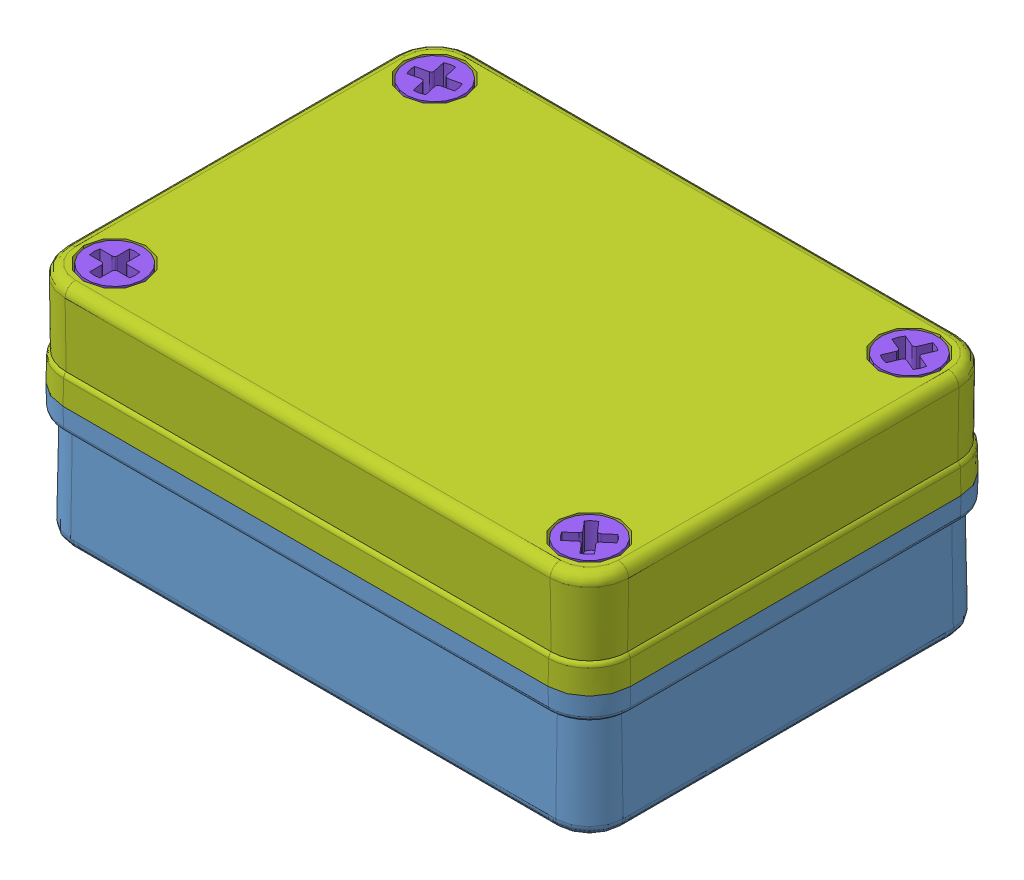
SolidWorks assembly _Adafruit_Feather_enclosure, configuration Default. Lengths in mm.
Overall size (110 46 80).
57 component instances, 26 part files, 18 mates.
Components (placement in the parent):
- KW_1643_bottom-1: KW_1643_bottom [Default] at origin size (110 28.2 80)
- 2926 Terminal Block Breakout FeatherWing-1: 2926 Terminal Block Breakout FeatherWing [Default] at (0 3.215 0) size (67.5 15.2 50.8)
  - 2926 Terminal Block Breakout FeatherWing-1: 2926 Terminal Block Breakout FeatherWing [Default] at origin size (67.5 6.27 50.8)
  - screw_terminal_16x_3.5pitch-1: screw_terminal_16x_3.5pitch [Default] at (-28 1.57 14.4) x (0 0 1) z (-1 0 0) size (7 12.2 56)
  - screw_terminal_16x_3.5pitch-2: screw_terminal_16x_3.5pitch [Default] at (28 1.57 -14.4) x (0 0 -1) z (1 0 0) size (7 12.2 56)
  - header_f16_tall-1: header_f16_tall [Default] at (-20.445 1.57 10.16) size (40.89 14.4 2.5)
  - header_f12_tall-1: header_f12_tall [Default] at (-10.285 1.57 -10.16) size (30.73 14.4 2.5)
- bracket_3D_printed-1: bracket_3D_printed [Default] at (-44.1 1 0) size (15 9.8 54)
- bracket_3D_printed-2: bracket_3D_printed [Default] at (44.1 1 0) x (-1 0 0) z (0 0 -1) size (15 9.8 54)
- KW_1643_top-2: KW_1643_top [Default] at origin size (110 36.5 80)
  - KW_1643_top-1: KW_1643_top [Default] at (0 25 0) x (-1 0 0) z (0 0 1) size (110 21.5 80)
  - KW_1643_screw-1: KW_1643_screw [Default] at (-46 45 -31) x (0.975576 0 -0.219664) z (0.219664 0 0.975576) size (11 36.5 11)
  - KW_1643_screw-2: KW_1643_screw [Default] at (-46 45 31) size (11 36.5 11)
  - KW_1643_screw-3: KW_1643_screw [Default] at (46 45 -31) x (0.38812 0 -0.921609) z (0.921609 0 0.38812) size (11 36.5 11)
  - KW_1643_screw-4: KW_1643_screw [Default] at (46 45 31) x (0.65086 0 0.759198) z (-0.759198 0 0.65086) size (11 36.5 11)
- 3857 Adafruit Feather M4 Express headers-1: 3857 Adafruit Feather M4 Express headers [Default] at (-25.4 18.685 11.43) x (1 0 0) z (0 1 0) size (50.85 22.86 14.87)
  - 3857 Adafruit Feather M4 Express-1: 3857 Adafruit Feather M4 Express [Default] at origin size (50.85 22.86 6.37)
    - 3857 Adafruit Feather M4 Express(2)^3857 Adafruit Feather M4 Express-1: 3857 Adafruit Feather M4 Express(2)^3857 Adafruit Feather M4 Express [Default] at origin size (50.85 22.86 6.37) (virtual)
      - PCB Component^3857 Adafruit Feather M4 Express(2)_3857 Adafruit Feather M4 Express-1: PCB Component^3857 Adafruit Feather M4 Express(2)_3857 Adafruit Feather M4 Express [Default] at origin size (50.85 22.86 6.37) (virtual)
        - Board^PCB Component_3857 Adafruit Feather M4 Express(2)_3857 Adafruit Feather M4 Express-1: Board^PCB Component_3857 Adafruit Feather M4 Express(2)_3857 Adafruit Feather M4 Express [Default] at origin size (50.8 22.86 1.57) (virtual)
        - 10uF^PCB Component_3857 Adafruit Feather M4 Express(2)_3857 Adafruit Feather M4 Express-1: 10uF^PCB Component_3857 Adafruit Feather M4 Express(2)_3857 Adafruit Feather M4 Express [Default] at (12.042 9.838 1.57) x (0 -1 0) z (0 0 1) size (2 1.25 1) (virtual)
        - 10uF^PCB Component_3857 Adafruit Feather M4 Express(2)_3857 Adafruit Feather M4 Express-2: 10uF^PCB Component_3857 Adafruit Feather M4 Express(2)_3857 Adafruit Feather M4 Express [Default] at (14.728 13.858 1.57) size (2 1.25 1) (virtual)
        - 10uF^PCB Component_3857 Adafruit Feather M4 Express(2)_3857 Adafruit Feather M4 Express-3: 10uF^PCB Component_3857 Adafruit Feather M4 Express(2)_3857 Adafruit Feather M4 Express [Default] at (15.748 17.272 1.57) x (0 -1 0) z (0 0 1) size (2 1.25 1) (virtual)
        - 10uF^PCB Component_3857 Adafruit Feather M4 Express(2)_3857 Adafruit Feather M4 Express-4: 10uF^PCB Component_3857 Adafruit Feather M4 Express(2)_3857 Adafruit Feather M4 Express [Default] at (35.065 18.669 1.57) size (2 1.25 1) (virtual)
        - 10uF^PCB Component_3857 Adafruit Feather M4 Express(2)_3857 Adafruit Feather M4 Express-5: 10uF^PCB Component_3857 Adafruit Feather M4 Express(2)_3857 Adafruit Feather M4 Express [Default] at (18.796 11.303 1.57) x (0 -1 0) z (0 0 1) size (2 1.25 1) (virtual)
        - 1uF^PCB Component_3857 Adafruit Feather M4 Express(2)_3857 Adafruit Feather M4 Express-1: 1uF^PCB Component_3857 Adafruit Feather M4 Express(2)_3857 Adafruit Feather M4 Express [Default] at (24.909 17.78 1.57) x (0 1 0) z (0 0 1) size (1.6 0.9 0.8) (virtual)
        - 1uF^PCB Component_3857 Adafruit Feather M4 Express(2)_3857 Adafruit Feather M4 Express-2: 1uF^PCB Component_3857 Adafruit Feather M4 Express(2)_3857 Adafruit Feather M4 Express [Default] at (11.989 4.218 1.57) size (1.6 0.9 0.8) (virtual)
        - 1uF^PCB Component_3857 Adafruit Feather M4 Express(2)_3857 Adafruit Feather M4 Express-3: 1uF^PCB Component_3857 Adafruit Feather M4 Express(2)_3857 Adafruit Feather M4 Express [Default] at (5.715 20.955 1.57) x (0 -1 0) z (0 0 1) size (1.6 0.9 0.8) (virtual)
        - 1uF^PCB Component_3857 Adafruit Feather M4 Express(2)_3857 Adafruit Feather M4 Express-4: 1uF^PCB Component_3857 Adafruit Feather M4 Express(2)_3857 Adafruit Feather M4 Express [Default] at (5.829 4.254 1.57) size (1.6 0.9 0.8) (virtual)
        - 1uF^PCB Component_3857 Adafruit Feather M4 Express(2)_3857 Adafruit Feather M4 Express-5: 1uF^PCB Component_3857 Adafruit Feather M4 Express(2)_3857 Adafruit Feather M4 Express [Default] at (18.415 17.97 1.57) size (1.6 0.9 0.8) (virtual)
        - 1uF^PCB Component_3857 Adafruit Feather M4 Express(2)_3857 Adafruit Feather M4 Express-6: 1uF^PCB Component_3857 Adafruit Feather M4 Express(2)_3857 Adafruit Feather M4 Express [Default] at (19.202 5.067 1.57) x (0 1 0) z (0 0 1) size (1.6 0.9 0.8) (virtual)
        - 1uF^PCB Component_3857 Adafruit Feather M4 Express(2)_3857 Adafruit Feather M4 Express-7: 1uF^PCB Component_3857 Adafruit Feather M4 Express(2)_3857 Adafruit Feather M4 Express [Default] at (21.526 6.35 1.57) x (-1 0 0) z (0 0 1) size (1.6 0.9 0.8) (virtual)
        - 1uF^PCB Component_3857 Adafruit Feather M4 Express(2)_3857 Adafruit Feather M4 Express-8: 1uF^PCB Component_3857 Adafruit Feather M4 Express(2)_3857 Adafruit Feather M4 Express [Default] at (36.119 4.648 1.57) x (-1 0 0) z (0 0 1) size (1.6 0.9 0.8) (virtual)
        - 1uF^PCB Component_3857 Adafruit Feather M4 Express(2)_3857 Adafruit Feather M4 Express-9: 1uF^PCB Component_3857 Adafruit Feather M4 Express(2)_3857 Adafruit Feather M4 Express [Default] at (19.126 8.065 1.57) x (0 1 0) z (0 0 1) size (1.6 0.9 0.8) (virtual)
        - 1uF^PCB Component_3857 Adafruit Feather M4 Express(2)_3857 Adafruit Feather M4 Express-10: 1uF^PCB Component_3857 Adafruit Feather M4 Express(2)_3857 Adafruit Feather M4 Express [Default] at (29.662 5.263 1.57) x (-1 0 0) z (0 0 1) size (1.6 0.9 0.8) (virtual)
        - 1uF^PCB Component_3857 Adafruit Feather M4 Express(2)_3857 Adafruit Feather M4 Express-11: 1uF^PCB Component_3857 Adafruit Feather M4 Express(2)_3857 Adafruit Feather M4 Express [Default] at (8.89 4.254 1.57) x (-1 0 0) z (0 0 1) size (1.6 0.9 0.8) (virtual)
        - 1uF^PCB Component_3857 Adafruit Feather M4 Express(2)_3857 Adafruit Feather M4 Express-12: 1uF^PCB Component_3857 Adafruit Feather M4 Express(2)_3857 Adafruit Feather M4 Express [Default] at (17.145 10.922 1.57) x (0 1 0) z (0 0 1) size (1.6 0.9 0.8) (virtual)
        - 1uF^PCB Component_3857 Adafruit Feather M4 Express(2)_3857 Adafruit Feather M4 Express-13: 1uF^PCB Component_3857 Adafruit Feather M4 Express(2)_3857 Adafruit Feather M4 Express [Default] at (13.856 6.502 1.57) x (0 -1 0) z (0 0 1) size (1.6 0.9 0.8) (virtual)
        - 1uF^PCB Component_3857 Adafruit Feather M4 Express(2)_3857 Adafruit Feather M4 Express-14: 1uF^PCB Component_3857 Adafruit Feather M4 Express(2)_3857 Adafruit Feather M4 Express [Default] at (21.4 8.065 1.57) size (1.6 0.9 0.8) (virtual)
        - 1uF^PCB Component_3857 Adafruit Feather M4 Express(2)_3857 Adafruit Feather M4 Express-15: 1uF^PCB Component_3857 Adafruit Feather M4 Express(2)_3857 Adafruit Feather M4 Express [Default] at (22.225 14.414 1.57) x (-1 0 0) z (0 0 1) size (1.6 0.9 0.8) (virtual)
        - ORANGE^PCB Component_3857 Adafruit Feather M4 Express(2)_3857 Adafruit Feather M4 Express-1: ORANGE^PCB Component_3857 Adafruit Feather M4 Express(2)_3857 Adafruit Feather M4 Express [Default] at (2.645 17.359 1.57) x (0 1 0) z (0 0 1) size (1.25 2.02 1.1) (virtual)
        - ORANGE^PCB Component_3857 Adafruit Feather M4 Express(2)_3857 Adafruit Feather M4 Express-2: ORANGE^PCB Component_3857 Adafruit Feather M4 Express(2)_3857 Adafruit Feather M4 Express [Default] at (2.413 5.588 1.57) x (0 -1 0) z (0 0 1) size (1.25 2.02 1.1) (virtual)
        - KMR2^PCB Component_3857 Adafruit Feather M4 Express(2)_3857 Adafruit Feather M4 Express-1: KMR2^PCB Component_3857 Adafruit Feather M4 Express(2)_3857 Adafruit Feather M4 Express [Default] at (9.398 6.54 1.57) x (-1 0 0) z (0 0 1) size (4.6 2.8 1.94) (virtual)
        - microUSB^PCB Component_3857 Adafruit Feather M4 Express(2)_3857 Adafruit Feather M4 Express-1: microUSB^PCB Component_3857 Adafruit Feather M4 Express(2)_3857 Adafruit Feather M4 Express [Default] at (4.445 11.43 1.57) x (0 -1 0) z (0 0 1) size (8.8 5.6 3) (virtual)
        - MCP73831T-2ACI_OT^PCB Component_3857 Adafruit Feather M4 Express(2)_3857 Adafruit Feather M4 Express-1: MCP73831T-2ACI_OT^PCB Component_3857 Adafruit Feather M4 Express(2)_3857 Adafruit Feather M4 Express [Default] at (14.732 10.922 1.57) size (3 3 1.4) (virtual)
        - MCP73831T-2ACI_OT^PCB Component_3857 Adafruit Feather M4 Express(2)_3857 Adafruit Feather M4 Express-2: MCP73831T-2ACI_OT^PCB Component_3857 Adafruit Feather M4 Express(2)_3857 Adafruit Feather M4 Express [Default] at (18.352 15.113 1.57) size (3 3 1.4) (virtual)
        - JSTPH^PCB Component_3857 Adafruit Feather M4 Express(2)_3857 Adafruit Feather M4 Express-1: JSTPH^PCB Component_3857 Adafruit Feather M4 Express(2)_3857 Adafruit Feather M4 Express [Default] at (10.795 19.304 1.57) size (7.9 8.6 4.8) (virtual)
        - 32.768^PCB Component_3857 Adafruit Feather M4 Express(2)_3857 Adafruit Feather M4 Express-1: 32.768^PCB Component_3857 Adafruit Feather M4 Express(2)_3857 Adafruit Feather M4 Express [Default] at (21.806 4.496 1.57) x (-1 0 0) z (0 0 1) size (3.5 1.5 0.8) (virtual)
        - WS2812B3535^PCB Component_3857 Adafruit Feather M4 Express(2)_3857 Adafruit Feather M4 Express-1: WS2812B3535^PCB Component_3857 Adafruit Feather M4 Express(2)_3857 Adafruit Feather M4 Express [Default] at (16.485 6.109 1.57) x (0 -1 0) z (0 0 1) size (3.5 3.5 1.2) (virtual)
        - 2MB Flash^PCB Component_3857 Adafruit Feather M4 Express(2)_3857 Adafruit Feather M4 Express-1: 2MB Flash^PCB Component_3857 Adafruit Feather M4 Express(2)_3857 Adafruit Feather M4 Express [Default] at (36.512 8.433 1.57) x (0 1 0) z (0 0 1) size (3 2 0.8) (virtual)
        - MBR120^PCB Component_3857 Adafruit Feather M4 Express(2)_3857 Adafruit Feather M4 Express-1: MBR120^PCB Component_3857 Adafruit Feather M4 Express(2)_3857 Adafruit Feather M4 Express [Default] at (10.35 12.319 1.57) x (-1 0 0) z (0 0 1) size (3.6 1.4 1.35) (virtual)
        - DMG341^PCB Component_3857 Adafruit Feather M4 Express(2)_3857 Adafruit Feather M4 Express-1: DMG341^PCB Component_3857 Adafruit Feather M4 Express(2)_3857 Adafruit Feather M4 Express [Default] at (9.398 9.842 1.57) size (3.04 2.64 1.12) (virtual)
        - 100K^PCB Component_3857 Adafruit Feather M4 Express(2)_3857 Adafruit Feather M4 Express-1: 100K^PCB Component_3857 Adafruit Feather M4 Express(2)_3857 Adafruit Feather M4 Express [Default] at (22.67 17.208 1.57) x (0 1 0) z (0 0 1) size (3.05 1.6 0.5) (virtual)
        - ATSAMD51J^PCB Component_3857 Adafruit Feather M4 Express(2)_3857 Adafruit Feather M4 Express-1: ATSAMD51J^PCB Component_3857 Adafruit Feather M4 Express(2)_3857 Adafruit Feather M4 Express [Default] at (30.162 11.049 1.57) x (0 1 0) z (0 0 1) size (9 9 0.8) (virtual)
        - 10uH^PCB Component_3857 Adafruit Feather M4 Express(2)_3857 Adafruit Feather M4 Express-1: 10uH^PCB Component_3857 Adafruit Feather M4 Express(2)_3857 Adafruit Feather M4 Express [Default] at (21.082 11.811 1.57) x (0 -1 0) z (0 0 1) size (2.7 2 2) (virtual)
  - header_m16-1: header_m16 [Default] at (5.08 1.27 -2.5) x (1 0 0) z (0 -1 0) size (40.64 11.5 2.5)
  - header_m12-1: header_m12 [Default] at (15.24 21.59 -2.5) x (1 0 0) z (0 -1 0) size (30.48 11.5 2.5)
Mates (geometry in assembly coordinates):
- Coincident1: coincident aligned: plane of bottom-1 through (0 0 0) normal (0 0 1)
- Coincident2: coincident aligned: plane of bottom-1 through (0 0 0) normal (0 1 0)
- Coincident3: coincident aligned: plane of bottom-1 through (0 0 0) normal (1 0 0)
- Coincident6: coincident anti-aligned: plane of bottom-1 through (0 7.8 0) normal (0 1 0); plane of bracket_3D_printed-1 through (-36.1 7.8 27) normal (0 -1 0)
- Concentric1: concentric anti-aligned: cylinder of bottom-1 through (-40.1 7.8 0) axis (0 1 0) radius 1.65; cylinder of bracket_3D_printed-1 through (-40.1 10.8 0) axis (0 -1 0) radius 2.05
- Parallel1: parallel aligned: plane of bracket_3D_printed-1 through (-44.1 1 0) normal (1 0 0)
- Coincident8: coincident anti-aligned: plane of bottom-1 through (0 7.8 0) normal (0 1 0); plane of bracket_3D_printed-2 through (36.1 7.8 -27) normal (0 -1 0)
- Concentric2: concentric anti-aligned: cylinder of bottom-1 through (40.1 7.8 0) axis (0 1 0) radius 1.65; cylinder of bracket_3D_printed-2 through (40.1 10.8 0) axis (0 -1 0) radius 2.05
- Parallel2: parallel anti-aligned: plane of bracket_3D_printed-2 through (44.1 1 0) normal (-1 0 0)
- Coincident14: coincident aligned: plane of KW_1643_bottom-1 through (0 0 0) normal (0 0 1); plane of 2926 Terminal Block Breakout FeatherWing-1 through (0 3.215 0) normal (0 0 1)
- Coincident15: coincident aligned: plane of KW_1643_bottom-1 through (0 0 0) normal (1 0 0); plane of 2926 Terminal Block Breakout FeatherWing-1 through (0 3.215 0) normal (1 0 0)
- Width1: width aligned: plane of bracket_3D_printed-1 through (-87.23 3.125 25.55) normal (0 1 0); plane of 2926 Terminal Block Breakout FeatherWing-1/2926 Terminal Block Breakout FeatherWing-1 through (-87.23 4.875 25.55) normal (0 -1 0); plane of bracket_3D_printed-1 through (0 4.785 0) normal (0 1 0); plane of 2926 Terminal Block Breakout FeatherWing-1/2926 Terminal Block Breakout FeatherWing-1 through (0 3.215 0) normal (0 -1 0)
- Coincident16: coincident anti-aligned: plane of KW_1643_bottom-1 through (-47 25 32) normal (0 1 0); plane of Assem1^_Adafruit_Feather_enclosure-1/KW_1643_top-1 through (47 25 32) normal (0 -1 0)
- Concentric9: concentric aligned: cylinder of KW_1643_bottom-1 through (-46 25 31) axis (0 1 0) radius 5.5; cylinder of Assem1^_Adafruit_Feather_enclosure-1/KW_1643_top-1 through (-46 34 31) axis (0 1 0) radius 6
- Concentric10: concentric aligned: cylinder of KW_1643_bottom-1 through (46 25 -31) axis (0 1 0) radius 5.5; cylinder of Assem1^_Adafruit_Feather_enclosure-1/KW_1643_top-1 through (46 34 -31) axis (0 1 0) radius 6
- Coincident17: coincident aligned: line of 2926 Terminal Block Breakout FeatherWing-1/header_f16_tall-1 through (-19.05 4.785 10.16) axis (0 -1 0); line of 3857 Adafruit Feather M4 Express headers-1/header_m16-1 through (-19.05 16.185 10.16) axis (0 -1 0)
- Coincident18: coincident aligned: line of 2926 Terminal Block Breakout FeatherWing-1/header_f16_tall-1 through (19.05 4.785 10.16) axis (0 -1 0); line of 3857 Adafruit Feather M4 Express headers-1/header_m16-1 through (19.05 16.185 10.16) axis (0 -1 0)
- Coincident19: coincident anti-aligned: plane of 2926 Terminal Block Breakout FeatherWing-1/header_f16_tall-1 through (-20.445 16.185 11.41) normal (0 1 0); plane of 3857 Adafruit Feather M4 Express headers-1/header_m16-1 through (-20.32 16.185 11.41) normal (0 -1 0)
